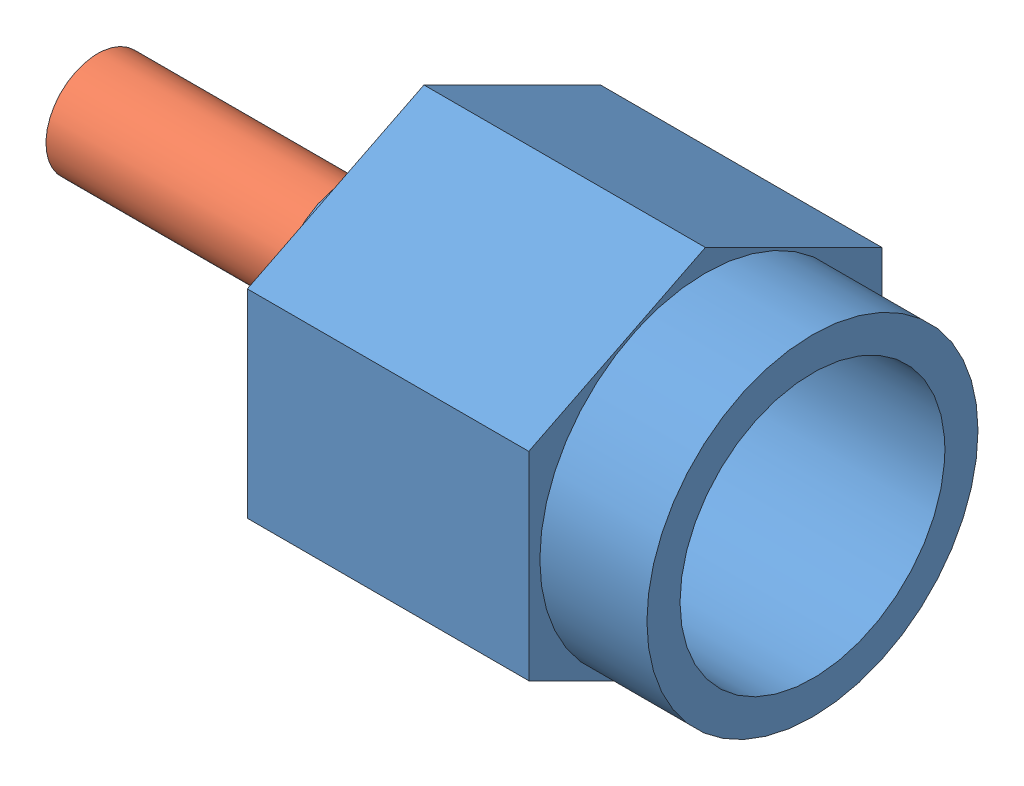
SolidWorks assembly Harness_7-avionics_asm, configuration 預設. Lengths in mm.
Overall size (19.45 8.64 8.13).
2 component instances, 2 part files, 2 mates.
Components (placement in the parent):
- plug-sma-1: plug-sma [Default] at (336.222 9 27) x (0 0 -1) z (1 0 0) size (8.13 8.64 19.45)
- 纜線^Harness_7-avionics_asm-1: 纜線^Harness_7-avionics_asm [預設] at origin size (7 2 2) (virtual)
Mates (geometry in assembly coordinates):
- 同軸心24491: concentric anti-aligned: cylinder of stick_antenna_asm-1/stick_antenna_434MHz-1 through (346.6 9 27) axis (1 0 0) radius 6.4; cylinder of plug-sma-1 through (338 9 27) axis (-1 0 0) radius 1.5367
- 重合/共線/共點941: coincident anti-aligned: plane of stick_antenna_asm-1/stick_antenna_434MHz-1 through (338 14.3579 23.4996) normal (-1 0 0); plane of plug-sma-1 through (338 9 27) normal (1 0 0)
